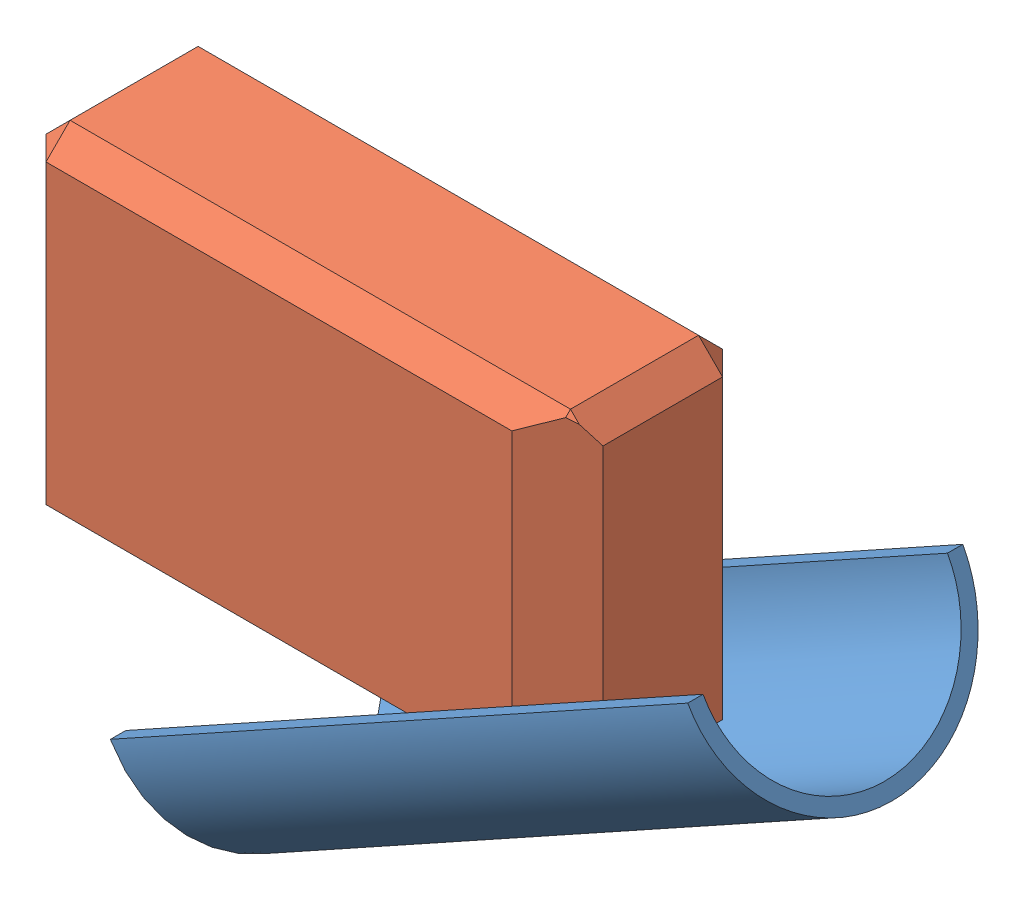
SolidWorks assembly Assem2, configuration Default. Lengths in mm.
2 component instances, 2 part files, 2 mates.
Components (placement in the parent):
- Part5^Assem2-1: Part5^Assem2 [Default] at origin size (267.66 182.99 114.3) (virtual)
- Foam Block cutted-1: Foam Block cutted [Default] at (128.5443 35.4414 -36.61) x (-1 0 0) z (0 1 0) size (228 73.22 143.36)
Mates (geometry in assembly coordinates):
- Parallel1: parallel anti-aligned: plane of Foam Block cutted-1 through (242.5443 -36.2386 36.61) normal (0 -1 0)
- Parallel2: parallel aligned: plane of Foam Block cutted-1 through (128.5443 35.4414 36.61) normal (0 0 1)
